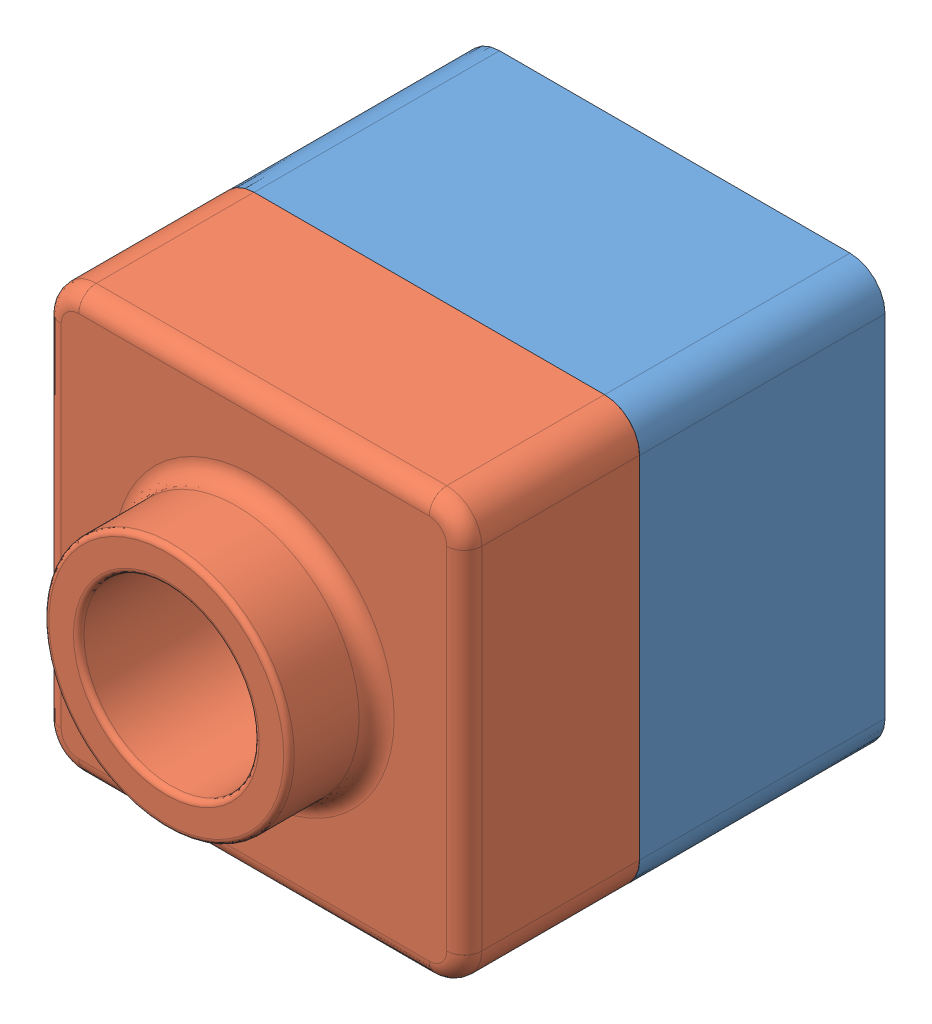
SolidWorks assembly ShellBoiAssembly, configuration Default. Lengths in mm.
Overall size (120.06 120 145).
2 component instances, 2 part files, 1 mates.
Components (placement in the parent):
- ShellBoi2-1: ShellBoi2 [Default] at (-2.825 41.8841 23.827) size (120 120 90)
- ShellBoi-2: ShellBoi [Default] at (-2.883 41.8841 93.827) size (120 120 75)
Mates (geometry in assembly coordinates):
- Coincident6: coincident aligned: line of ShellBoi-2 through (47.117 101.8841 93.827) axis (-1 0 0); line of ShellBoi2-1 through (47.175 101.8841 93.827) axis (-1 0 0)
